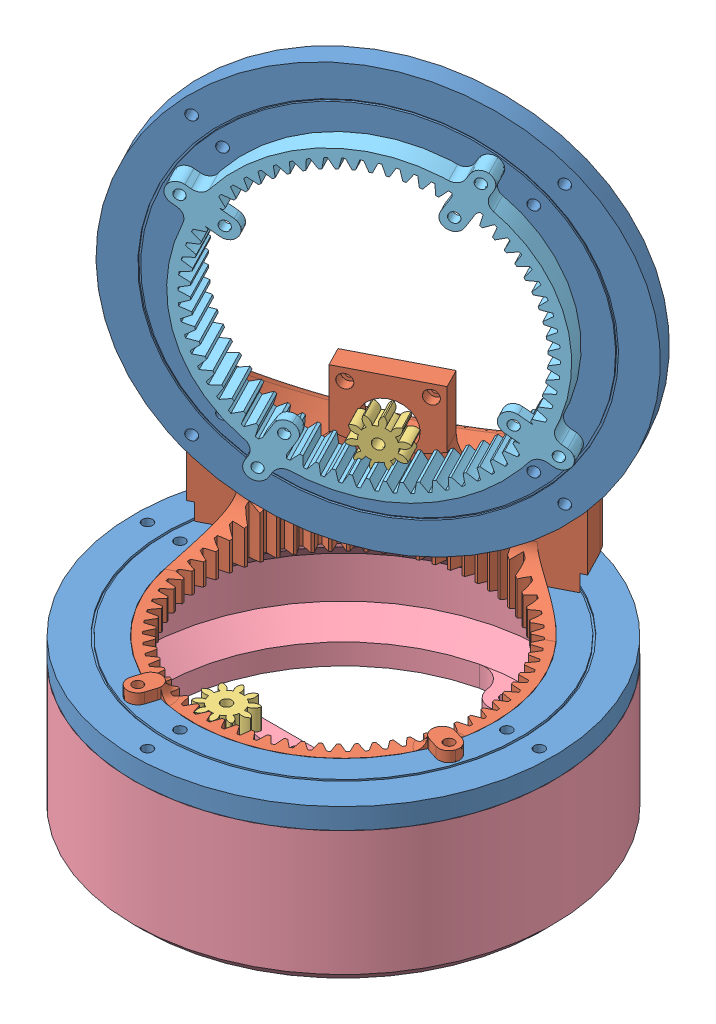
SolidWorks assembly full_assem, configuration Default. Lengths in mm.
Overall size (258.78 327.88 224.14).
9 component instances, 5 part files, 24 mates.
Components (placement in the parent):
- turntable_assem-2: turntable_assem [Default] at (178.1131 273.6145 15.5653) x (-1 0 0) z (0 0 1) size (202.06 10 202.06)
  - slew_ring-1: slew_ring [Default] at (74.757 113.3639 146.6699) size (202.06 10 202.06)
- turntable_assem-3: turntable_assem [Default] at (276.7416 321.1008 157.1435) x (-0.629056 0.707107 0.322937) z (-0.629056 -0.707107 0.322937) size (202.06 10 202.06)
  - slew_ring-1: slew_ring [Default] at (74.757 113.3639 146.6699) size (202.06 10 202.06)
- pitch_yaw_frame-1: pitch_yaw_frame [Default] at (109.6747 160.2507 28.3648) x (-0.88962 0 0.456702) z (-0.456702 0 -0.88962) size (145 85 173.53)
- spur gear_am-1: spur gear_am [Metric - Spur gear 2M 10T 20PA 10FW ---S10N75H50L5N] at (103.3561 160.2507 218.5652) x (0 -1 0) z (-0.301117 0 -0.953587) size (10 22.98 24)
- nema17_base-1: nema17_base [Default] at (103.3561 140.2507 162.2352) size (202.3 65 202.3)
- spur gear_am-2: spur gear_am [Metric - Spur gear 2M 10T 20PA 10FW ---S10N75H50L5N] at (81.1111 214.1007 118.9036) x (0.456702 0 0.88962) z (-0.881216 -0.137128 0.452388) size (10 22.98 24)
- pitch_gear-1: pitch_gear [Default] at (47.9497 254.1055 133.6136) x (0.456702 0 0.88962) z (-0.766645 0.507305 0.393571) size (20 168.95 168.95)
Mates (geometry in assembly coordinates):
- Concentric1: concentric aligned: cylinder of turntable_assem-2/slew_ring-1 through (197.7698 160.2507 162.2352) axis (0 -1 0) radius 2.5; cylinder of pitch_yaw_corner-1 through (197.7698 218.2507 162.2352) axis (0 -1 0) radius 2.4
- Coincident9: coincident anti-aligned: plane of turntable_assem-2/slew_ring-1 through (103.3561 160.2507 162.2352) normal (0 1 0); plane of pitch_yaw_corner-1 through (197.7698 160.2507 162.2352) normal (0 -1 0)
- Concentric3: concentric aligned: cylinder of turntable_assem-2/slew_ring-1 through (103.3561 160.2507 256.6489) axis (0 -1 0) radius 2.5; cylinder of pitch_yaw_corner-2 through (103.3561 218.2507 256.6489) axis (0 -1 0) radius 2.4
- Coincident10: coincident anti-aligned: plane of turntable_assem-2/slew_ring-1 through (103.3561 160.2507 162.2352) normal (0 1 0); plane of pitch_yaw_corner-2 through (103.3561 160.2507 256.6489) normal (0 -1 0)
- Concentric5: concentric aligned: cylinder of turntable_assem-2/slew_ring-1 through (103.3561 150.2507 162.2352) axis (0 1 0) radius 101.0285; cylinder of pitch_yaw_frame-1 through (103.3561 160.2507 162.2352) axis (0 1 0) radius 101.03
- Coincident14: coincident anti-aligned: plane of turntable_assem-3/slew_ring-1 through (81.1111 270.2507 118.9036) normal (-0.456702 0 -0.88962); plane of pitch_yaw_frame-1 through (144.9502 160.2507 86.1306) normal (0.456702 0 0.88962)
- Coincident13: coincident anti-aligned: plane of turntable_assem-2/slew_ring-1 through (103.3561 160.2507 162.2352) normal (0 1 0); plane of pitch_yaw_frame-1 through (109.6747 160.2507 28.3648) normal (0 -1 0)
- Angle1: planar angle = 0.785398 rad anti-aligned: plane of turntable_assem-3/slew_ring-1 through (85.6781 270.2507 127.7998) normal (-0.629056 -0.707107 0.322937); plane of pitch_yaw_frame-1 through (109.6747 160.2507 28.3648) normal (0 1 0)
- Coincident16: coincident: line of turntable_assem-3/slew_ring-1 through (81.1111 270.2507 118.9036) axis (0.456702 0 0.88962); plane of pitch_yaw_frame-1 through (109.6747 270.2507 28.3648) normal (0 -1 0)
- Coincident17: coincident: line of turntable_assem-3/slew_ring-1 through (81.1111 270.2507 118.9036) axis (0.456702 0 0.88962); plane of pitch_yaw_frame-1 through (50.2837 160.2507 58.8542) normal (0.88962 0 -0.456702)
- Concentric6: concentric aligned: cylinder of turntable_assem-3/slew_ring-1 through (81.1111 270.2507 118.9036) axis (0.456702 0 0.88962) radius 72.6313; cylinder of internal spur gear_am-1 through (130.8941 270.2507 170.3475) axis (-0.959243 0 -0.282582) radius 72.5
- Coincident18: coincident aligned: plane of turntable_assem-3/slew_ring-1 through (85.6781 270.2507 127.7998) normal (0.456702 0 0.88962); plane of internal spur gear_am-1 through (131.437 214.839 203.8923) normal (-0.959243 0 -0.282582)
- Coincident19: coincident aligned: plane of pitch_yaw_frame-1 through (132.5851 160.2507 219.1708) normal (0 1 0); plane of spur gear_am-1 through (103.3561 160.2507 218.5652) normal (0 1 0)
- GearMate2: gear = 10 : 66 mm: circle of pitch_yaw_frame-1; circle of stepper_drive_gear-1
- Concentric8: concentric: cylinder of turntable_assem-2/slew_ring-1 through (103.3561 150.2507 162.2352) axis (0 1 0) radius 101.0285; point of nema17_base-1
- Perpendicular1: perpendicular: plane of nema17_base-1 through (80.8561 135.2507 196.0652) normal (-1 0 0)
- Concentric9: concentric aligned: cylinder of spur gear_am-1 through (103.3561 110.2506 218.5652) axis (0 1 0) radius 2.5; circle of nema17_base-1
- Coincident24: coincident anti-aligned: plane of pitch_yaw_frame-1 through (144.9502 160.2507 86.1306) normal (0.456702 0 0.88962); plane of spur gear_am-2 through (81.1111 214.1007 118.9036) normal (-0.456702 0 -0.88962)
- Concentric10: concentric anti-aligned: circle of pitch_yaw_frame-1; cylinder of spur gear_am-2 through (103.9462 214.1007 163.3846) axis (-0.456702 0 -0.88962) radius 2.5
- Concentric11: concentric anti-aligned: cylinder of turntable_assem-3/slew_ring-1 through (81.1111 270.2507 118.9036) axis (0.456702 0 0.88962) radius 72.6313; cylinder of pitch_gear-1 through (76.5441 270.2507 110.0074) axis (-0.456702 0 -0.88962) radius 72.5
- Coincident25: coincident anti-aligned: plane of turntable_assem-3/slew_ring-1 through (85.6781 270.2507 127.7998) normal (0.456702 0 0.88962); plane of pitch_gear-1 through (85.6781 270.2507 127.7998) normal (-0.456702 0 -0.88962)
- Concentric12: concentric aligned: cylinder of turntable_assem-2/slew_ring-1 through (103.3561 150.2507 162.2352) axis (0 1 0) radius 101.0285; cylinder of foot-1 through (103.3561 100.2507 162.2352) axis (0 1 0) radius 101.0285
- Coincident26: coincident anti-aligned: plane of turntable_assem-2/slew_ring-1 through (103.3561 150.2507 162.2352) normal (0 -1 0); plane of foot-1 through (155.5565 150.2507 162.0657) normal (0 1 0)
- Coincident27: coincident anti-aligned: plane of turntable_assem-2/slew_ring-1 through (103.3561 150.2507 162.2352) normal (0 -1 0); plane of nema17_base-1 through (103.3561 150.2507 162.2352) normal (0 1 0)
